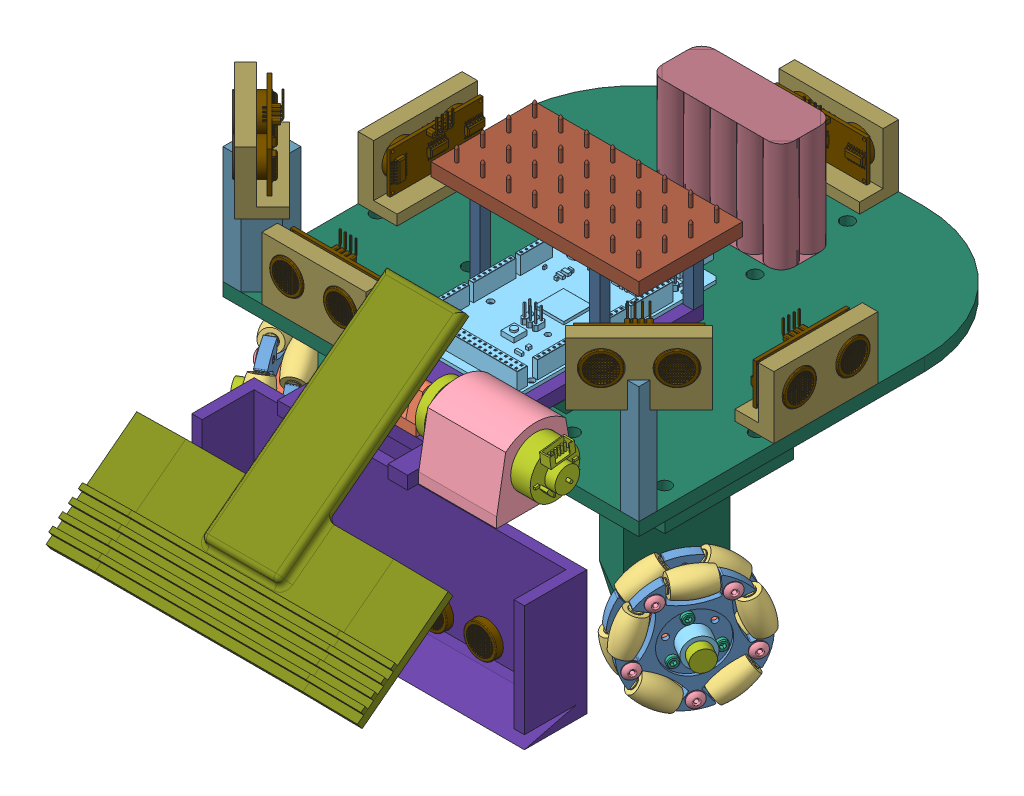
SolidWorks assembly Final_Assem_v2, configuration Default. Lengths in mm.
Overall size (261.62 184.22 333.49).
163 component instances, 35 part files, 105 mates.
Components (placement in the parent):
- WheelAsm-1: WheelAsm [Default] at (163.9905 -186.0529 158.5442) x (-0.148791 -0.954696 0.257713) z (-0.866025 0 -0.5) size (63.86 60.79 27.6)
  - WheelBase-2: WheelBase [Default] at (4.9023 2.731 55.3836) x (1 0 0) z (0 -1 0) size (56.86 5 54.96)
  - BasePlacer-1: BasePlacer [Default] at (4.9023 2.731 58.8836) x (1 0 0) z (0 -1 0) size (28 10 28)
  - RubberWheel-1: RubberWheel [Default] at (4.9023 26.7901 57.8836) x (1 0 0) z (0 -0.999594 -0.028494) size (19 12.5 12.5)
  - RubberWheel-2: RubberWheel [Default] at (-17.9792 10.1657 57.8836) x (0.309017 0.951057 0) z (0.95067 -0.308892 -0.028494) size (19 12.5 12.5)
  - RubberWheel-3: RubberWheel [Default] at (-9.2392 -16.7332 57.8836) x (-0.809017 0.587785 0) z (0.587547 0.808689 -0.028494) size (19 12.5 12.5)
  - RubberWheel-4: RubberWheel [Default] at (19.0439 -16.7332 57.8836) x (-0.809017 -0.587785 0) z (-0.587547 0.808689 -0.028494) size (19 12.5 12.5)
  - RubberWheel-5: RubberWheel [Default] at (27.7839 10.1657 57.8836) x (0.309017 -0.951057 0) z (-0.95067 -0.308892 -0.028494) size (19 12.5 12.5)
  - Rivet-1: Rivet [Default] at (4.9023 -21.269 54.8836) x (1 0 0) z (0 1 0) size (7.46 6.8 7.46)
  - Rivet-2: Rivet [Default] at (27.7277 -4.6854 54.8836) x (0.309017 0.951057 0) z (-0.951057 0.309017 0) size (7.46 6.8 7.46)
  - Rivet-3: Rivet [Default] at (19.0092 22.1474 54.8836) x (-0.809017 0.587785 0) z (-0.587785 -0.809017 0) size (7.46 6.8 7.46)
  - Rivet-4: Rivet [Default] at (-9.2045 22.1474 54.8836) x (-0.809017 -0.587785 0) z (0.587785 -0.809017 0) size (7.46 6.8 7.46)
  - Rivet-5: Rivet [Default] at (-17.923 -4.6854 54.8836) x (0.309017 -0.951057 0) z (0.951057 0.309017 0) size (7.46 6.8 7.46)
  - WheelBase-6: WheelBase [Default] at (4.9023 2.731 67.3836) x (-1 0 0) z (0 1 0) size (56.86 5 54.96)
  - RubberWheel-16: RubberWheel [Default] at (4.9023 -21.3281 69.8836) size (19 12.5 12.5)
  - RubberWheel-17: RubberWheel [Default] at (27.7839 -4.7037 69.8836) x (0.309017 0.951057 0) z (0 0 1) size (19 12.5 12.5)
  - RubberWheel-18: RubberWheel [Default] at (19.0439 22.1953 69.8836) x (-0.809017 0.587785 0) z (0 0 1) size (19 12.5 12.5)
  - RubberWheel-19: RubberWheel [Default] at (-9.2392 22.1953 69.8836) x (-0.809017 -0.587785 0) z (0 0 1) size (19 12.5 12.5)
  - RubberWheel-20: RubberWheel [Default] at (-17.9792 -4.7037 69.8836) x (0.309017 -0.951057 0) z (0 0 1) size (19 12.5 12.5)
  - Rivet-16: Rivet [Default] at (-9.2045 -16.6854 72.8836) x (-0.985624 0.168955 0) z (0.168955 0.985624 0) size (7.46 6.8 7.46)
  - Rivet-17: Rivet [Default] at (19.0092 -16.6854 72.8836) x (-0.46526 -0.885174 0) z (-0.885174 0.46526 0) size (7.46 6.8 7.46)
  - Rivet-18: Rivet [Default] at (27.7277 10.1474 72.8836) x (0.698077 -0.716022 0) z (-0.716022 -0.698077 0) size (7.46 6.8 7.46)
  - Rivet-19: Rivet [Default] at (4.9023 26.731 72.8836) x (0.896695 0.442648 0) z (0.442648 -0.896695 0) size (7.46 6.8 7.46)
  - Rivet-20: Rivet [Default] at (-17.923 10.1474 72.8836) x (-0.143889 0.989594 0) z (0.989594 0.143889 0) size (7.46 6.8 7.46)
  - ShaftConnector-1: ShaftConnector [Default] at (4.9023 2.731 48.8836) x (1 0 0) z (0 -1 0) size (14 27.6 14)
  - Part7^WheelAsm-1: Part7^WheelAsm [Default] at origin (virtual)
  - Part8^WheelAsm-1: Part8^WheelAsm [Default] at origin (virtual)
  - M3HexNut-1: M3HexNut [Default] at (13.9956 7.981 72.8836) x (1 0 0) z (0 0 -1) size (5 5 5)
  - M3HexNut-2: M3HexNut [Default] at (-4.1909 7.981 72.8836) x (-0.5 0.866025 0) z (0 0 -1) size (5 5 5)
  - M3HexNut-3: M3HexNut [Default] at (4.9023 -7.769 72.8836) x (-0.5 -0.866025 0) z (0 0 -1) size (5 5 5)
  - M3HexNut-4: M3HexNut [Default] at (4.9023 -7.769 54.8836) size (5 5 5)
  - M3HexNut-5: M3HexNut [Default] at (13.9956 7.981 54.8836) x (-0.5 0.866025 0) z (0 0 1) size (5 5 5)
  - M3HexNut-6: M3HexNut [Default] at (-4.1909 7.981 54.8836) x (-0.5 -0.866025 0) z (0 0 1) size (5 5 5)
- WheelAsm-2: WheelAsm [Default] at (14.2994 -187.213 -102.2458) x (-0.999988 0.004806 0) z (0 0 1) size (63.86 60.79 27.6)
  - WheelBase-2: WheelBase [Default] at (4.9023 2.731 55.3836) x (1 0 0) z (0 -1 0) size (56.86 5 54.96)
  - BasePlacer-1: BasePlacer [Default] at (4.9023 2.731 58.8836) x (1 0 0) z (0 -1 0) size (28 10 28)
  - RubberWheel-1: RubberWheel [Default] at (4.9023 26.7901 57.8836) x (1 0 0) z (0 -0.999594 -0.028494) size (19 12.5 12.5)
  - RubberWheel-2: RubberWheel [Default] at (-17.9792 10.1657 57.8836) x (0.309017 0.951057 0) z (0.95067 -0.308892 -0.028494) size (19 12.5 12.5)
  - RubberWheel-3: RubberWheel [Default] at (-9.2392 -16.7332 57.8836) x (-0.809017 0.587785 0) z (0.587547 0.808689 -0.028494) size (19 12.5 12.5)
  - RubberWheel-4: RubberWheel [Default] at (19.0439 -16.7332 57.8836) x (-0.809017 -0.587785 0) z (-0.587547 0.808689 -0.028494) size (19 12.5 12.5)
  - RubberWheel-5: RubberWheel [Default] at (27.7839 10.1657 57.8836) x (0.309017 -0.951057 0) z (-0.95067 -0.308892 -0.028494) size (19 12.5 12.5)
  - Rivet-1: Rivet [Default] at (4.9023 -21.269 54.8836) x (1 0 0) z (0 1 0) size (7.46 6.8 7.46)
  - Rivet-2: Rivet [Default] at (27.7277 -4.6854 54.8836) x (0.309017 0.951057 0) z (-0.951057 0.309017 0) size (7.46 6.8 7.46)
  - Rivet-3: Rivet [Default] at (19.0092 22.1474 54.8836) x (-0.809017 0.587785 0) z (-0.587785 -0.809017 0) size (7.46 6.8 7.46)
  - Rivet-4: Rivet [Default] at (-9.2045 22.1474 54.8836) x (-0.809017 -0.587785 0) z (0.587785 -0.809017 0) size (7.46 6.8 7.46)
  - Rivet-5: Rivet [Default] at (-17.923 -4.6854 54.8836) x (0.309017 -0.951057 0) z (0.951057 0.309017 0) size (7.46 6.8 7.46)
  - WheelBase-6: WheelBase [Default] at (4.9023 2.731 67.3836) x (-1 0 0) z (0 1 0) size (56.86 5 54.96)
  - RubberWheel-16: RubberWheel [Default] at (4.9023 -21.3281 69.8836) size (19 12.5 12.5)
  - RubberWheel-17: RubberWheel [Default] at (27.7839 -4.7037 69.8836) x (0.309017 0.951057 0) z (0 0 1) size (19 12.5 12.5)
  - RubberWheel-18: RubberWheel [Default] at (19.0439 22.1953 69.8836) x (-0.809017 0.587785 0) z (0 0 1) size (19 12.5 12.5)
  - RubberWheel-19: RubberWheel [Default] at (-9.2392 22.1953 69.8836) x (-0.809017 -0.587785 0) z (0 0 1) size (19 12.5 12.5)
  - RubberWheel-20: RubberWheel [Default] at (-17.9792 -4.7037 69.8836) x (0.309017 -0.951057 0) z (0 0 1) size (19 12.5 12.5)
  - Rivet-16: Rivet [Default] at (-9.2045 -16.6854 72.8836) x (-0.985624 0.168955 0) z (0.168955 0.985624 0) size (7.46 6.8 7.46)
  - Rivet-17: Rivet [Default] at (19.0092 -16.6854 72.8836) x (-0.46526 -0.885174 0) z (-0.885174 0.46526 0) size (7.46 6.8 7.46)
  - Rivet-18: Rivet [Default] at (27.7277 10.1474 72.8836) x (0.698077 -0.716022 0) z (-0.716022 -0.698077 0) size (7.46 6.8 7.46)
  - Rivet-19: Rivet [Default] at (4.9023 26.731 72.8836) x (0.896695 0.442648 0) z (0.442648 -0.896695 0) size (7.46 6.8 7.46)
  - Rivet-20: Rivet [Default] at (-17.923 10.1474 72.8836) x (-0.143889 0.989594 0) z (0.989594 0.143889 0) size (7.46 6.8 7.46)
  - ShaftConnector-1: ShaftConnector [Default] at (4.9023 2.731 48.8836) x (1 0 0) z (0 -1 0) size (14 27.6 14)
  - Part7^WheelAsm-1: Part7^WheelAsm [Default] at origin (virtual)
  - Part8^WheelAsm-1: Part8^WheelAsm [Default] at origin (virtual)
  - M3HexNut-1: M3HexNut [Default] at (13.9956 7.981 72.8836) x (1 0 0) z (0 0 -1) size (5 5 5)
  - M3HexNut-2: M3HexNut [Default] at (-4.1909 7.981 72.8836) x (-0.5 0.866025 0) z (0 0 -1) size (5 5 5)
  - M3HexNut-3: M3HexNut [Default] at (4.9023 -7.769 72.8836) x (-0.5 -0.866025 0) z (0 0 -1) size (5 5 5)
  - M3HexNut-4: M3HexNut [Default] at (4.9023 -7.769 54.8836) size (5 5 5)
  - M3HexNut-5: M3HexNut [Default] at (13.9956 7.981 54.8836) x (-0.5 0.866025 0) z (0 0 1) size (5 5 5)
  - M3HexNut-6: M3HexNut [Default] at (-4.1909 7.981 54.8836) x (-0.5 -0.866025 0) z (0 0 1) size (5 5 5)
- WheelAsm-3: WheelAsm [Default] at (-145.8609 -191.8955 157.5426) x (0.323209 0.762983 0.559814) z (0.866025 0 -0.5) size (63.86 60.79 27.6)
  - WheelBase-2: WheelBase [Default] at (4.9023 2.731 55.3836) x (1 0 0) z (0 -1 0) size (56.86 5 54.96)
  - BasePlacer-1: BasePlacer [Default] at (4.9023 2.731 58.8836) x (1 0 0) z (0 -1 0) size (28 10 28)
  - RubberWheel-1: RubberWheel [Default] at (4.9023 26.7901 57.8836) x (1 0 0) z (0 -0.999594 -0.028494) size (19 12.5 12.5)
  - RubberWheel-2: RubberWheel [Default] at (-17.9792 10.1657 57.8836) x (0.309017 0.951057 0) z (0.95067 -0.308892 -0.028494) size (19 12.5 12.5)
  - RubberWheel-3: RubberWheel [Default] at (-9.2392 -16.7332 57.8836) x (-0.809017 0.587785 0) z (0.587547 0.808689 -0.028494) size (19 12.5 12.5)
  - RubberWheel-4: RubberWheel [Default] at (19.0439 -16.7332 57.8836) x (-0.809017 -0.587785 0) z (-0.587547 0.808689 -0.028494) size (19 12.5 12.5)
  - RubberWheel-5: RubberWheel [Default] at (27.7839 10.1657 57.8836) x (0.309017 -0.951057 0) z (-0.95067 -0.308892 -0.028494) size (19 12.5 12.5)
  - Rivet-1: Rivet [Default] at (4.9023 -21.269 54.8836) x (1 0 0) z (0 1 0) size (7.46 6.8 7.46)
  - Rivet-2: Rivet [Default] at (27.7277 -4.6854 54.8836) x (0.309017 0.951057 0) z (-0.951057 0.309017 0) size (7.46 6.8 7.46)
  - Rivet-3: Rivet [Default] at (19.0092 22.1474 54.8836) x (-0.809017 0.587785 0) z (-0.587785 -0.809017 0) size (7.46 6.8 7.46)
  - Rivet-4: Rivet [Default] at (-9.2045 22.1474 54.8836) x (-0.809017 -0.587785 0) z (0.587785 -0.809017 0) size (7.46 6.8 7.46)
  - Rivet-5: Rivet [Default] at (-17.923 -4.6854 54.8836) x (0.309017 -0.951057 0) z (0.951057 0.309017 0) size (7.46 6.8 7.46)
  - WheelBase-6: WheelBase [Default] at (4.9023 2.731 67.3836) x (-1 0 0) z (0 1 0) size (56.86 5 54.96)
  - RubberWheel-16: RubberWheel [Default] at (4.9023 -21.3281 69.8836) size (19 12.5 12.5)
  - RubberWheel-17: RubberWheel [Default] at (27.7839 -4.7037 69.8836) x (0.309017 0.951057 0) z (0 0 1) size (19 12.5 12.5)
  - RubberWheel-18: RubberWheel [Default] at (19.0439 22.1953 69.8836) x (-0.809017 0.587785 0) z (0 0 1) size (19 12.5 12.5)
  - RubberWheel-19: RubberWheel [Default] at (-9.2392 22.1953 69.8836) x (-0.809017 -0.587785 0) z (0 0 1) size (19 12.5 12.5)
  - RubberWheel-20: RubberWheel [Default] at (-17.9792 -4.7037 69.8836) x (0.309017 -0.951057 0) z (0 0 1) size (19 12.5 12.5)
  - Rivet-16: Rivet [Default] at (-9.2045 -16.6854 72.8836) x (-0.985624 0.168955 0) z (0.168955 0.985624 0) size (7.46 6.8 7.46)
  - Rivet-17: Rivet [Default] at (19.0092 -16.6854 72.8836) x (-0.46526 -0.885174 0) z (-0.885174 0.46526 0) size (7.46 6.8 7.46)
  - Rivet-18: Rivet [Default] at (27.7277 10.1474 72.8836) x (0.698077 -0.716022 0) z (-0.716022 -0.698077 0) size (7.46 6.8 7.46)
  - Rivet-19: Rivet [Default] at (4.9023 26.731 72.8836) x (0.896695 0.442648 0) z (0.442648 -0.896695 0) size (7.46 6.8 7.46)
  - Rivet-20: Rivet [Default] at (-17.923 10.1474 72.8836) x (-0.143889 0.989594 0) z (0.989594 0.143889 0) size (7.46 6.8 7.46)
  - ShaftConnector-1: ShaftConnector [Default] at (4.9023 2.731 48.8836) x (1 0 0) z (0 -1 0) size (14 27.6 14)
  - Part7^WheelAsm-1: Part7^WheelAsm [Default] at origin (virtual)
  - Part8^WheelAsm-1: Part8^WheelAsm [Default] at origin (virtual)
  - M3HexNut-1: M3HexNut [Default] at (13.9956 7.981 72.8836) x (1 0 0) z (0 0 -1) size (5 5 5)
  - M3HexNut-2: M3HexNut [Default] at (-4.1909 7.981 72.8836) x (-0.5 0.866025 0) z (0 0 -1) size (5 5 5)
  - M3HexNut-3: M3HexNut [Default] at (4.9023 -7.769 72.8836) x (-0.5 -0.866025 0) z (0 0 -1) size (5 5 5)
  - M3HexNut-4: M3HexNut [Default] at (4.9023 -7.769 54.8836) size (5 5 5)
  - M3HexNut-5: M3HexNut [Default] at (13.9956 7.981 54.8836) x (-0.5 0.866025 0) z (0 0 1) size (5 5 5)
  - M3HexNut-6: M3HexNut [Default] at (-4.1909 7.981 54.8836) x (-0.5 -0.866025 0) z (0 0 1) size (5 5 5)
- 6V Motor Spin-1: 6V Motor Spin [Default] at (27.2733 -240.3712 40.8764) x (-0.886104 0.457845 -0.072098) z (0.080946 -0.000295 -0.996718) size (29.63 28.32 78.39)
  - Motor no spinny boi-1: Motor no spinny boi [Default] at (39.6165 36.3483 7.7453) x (0.997226 -0.015871 -0.072721) z (0.072098 -0.036799 0.996718) size (24.4 25.49 66.9)
  - Motor spinny boi-1: Motor spinny boi [Default] at (39.6165 36.3483 7.7453) x (0.547957 0.836461 -0.008754) z (0.072098 -0.036799 0.996718) size (3.95 3.95 13.05)
- DC Motor 12V-1: DC Motor 12V [Predeterminado] at (-53.9561 -189.9205 110.5467) x (0.5 0 0.866025) z (-0.866025 0 0.5) size (28.03 28 53.5)
  - Carcaça12V-1: Carcaça12V [Predeterminado] at (0 0 24.0663) size (28.03 28 32.04)
  - Bucha12V-1: Bucha12V [Predeterminado] at (0 0 26.0163) x (0.994754 0.102295 0) z (0 0 1) size (7 7 0.5)
  - Mancal12V-1: Mancal12V [Predeterminado] at (0 0 -2.9337) x (-1 0 0) z (0 0 -1) size (27.69 28 8)
  - Terminal12V-1: Terminal12V [Predeterminado] at (0 -11.5 -3.9337) x (1 0 0) z (0 1 0) size (2.9 10 0.4)
  - Terminal12V-2: Terminal12V [Predeterminado] at (0 11.5 -3.9337) x (1 0 0) z (0 1 0) size (2.9 10 0.4)
  - Eixo12V-1: Eixo12V [Predeterminado] at (0 0 39.5663) x (-0.33009 -0.943949 0) z (0 0 1) size (21 20.89 51)
  - Enrolamento12V-1: Enrolamento12V [Predeterminado] at (-5.1702 1.808 12.5663) x (0.33009 0.943949 0) z (0 0 1) size (10 3 20)
  - Enrolamento12V-2: Enrolamento12V [Predeterminado] at (1.0194 -5.3815 12.5663) x (-0.982529 -0.186108 0) z (0 0 1) size (10 3 20)
  - Enrolamento12V-3: Enrolamento12V [Predeterminado] at (4.1509 3.5736 12.5663) x (0.652439 -0.757841 0) z (0 0 1) size (10 3 20)
- DC Motor 12V-2: DC Motor 12V [Predeterminado] at (72.7137 -189.9205 110.5407) x (-0.212518 0.905176 0.368092) z (0.866025 0 0.5) size (28.03 28 53.5)
  - Carcaça12V-1: Carcaça12V [Predeterminado] at (0 0 24.0663) size (28.03 28 32.04)
  - Bucha12V-1: Bucha12V [Predeterminado] at (0 0 26.0163) x (0.994754 0.102295 0) z (0 0 1) size (7 7 0.5)
  - Mancal12V-1: Mancal12V [Predeterminado] at (0 0 -2.9337) x (-1 0 0) z (0 0 -1) size (27.69 28 8)
  - Terminal12V-1: Terminal12V [Predeterminado] at (0 -11.5 -3.9337) x (1 0 0) z (0 1 0) size (2.9 10 0.4)
  - Terminal12V-2: Terminal12V [Predeterminado] at (0 11.5 -3.9337) x (1 0 0) z (0 1 0) size (2.9 10 0.4)
  - Eixo12V-1: Eixo12V [Predeterminado] at (0 0 39.5663) x (-0.33009 -0.943949 0) z (0 0 1) size (21 20.89 51)
  - Enrolamento12V-1: Enrolamento12V [Predeterminado] at (-5.1702 1.808 12.5663) x (0.33009 0.943949 0) z (0 0 1) size (10 3 20)
  - Enrolamento12V-2: Enrolamento12V [Predeterminado] at (1.0194 -5.3815 12.5663) x (-0.982529 -0.186108 0) z (0 0 1) size (10 3 20)
  - Enrolamento12V-3: Enrolamento12V [Predeterminado] at (4.1509 3.5736 12.5663) x (0.652439 -0.757841 0) z (0 0 1) size (10 3 20)
- Acrylic Plate (square 12 inch) cut version-1: Acrylic Plate (square 12 inch) cut version [Default] at (9.384 -134.5485 57.0478) size (203.2 6.35 203.2)
- ScoopClawAssembly-1: ScoopClawAssembly [Default] at (-135.2234 -155.5644 109.464) size (171.3 138.74 218)
  - Scooper-1: Scooper [Default] at (144.6073 0.6103 138.0053) x (1 0 0) z (0 0.793599 0.608442) size (152.65 142.24 11.1)
  - Scooper_Base-1: Scooper_Base [Default] at (144.6073 -61.534 72.0438) size (162.56 95.25 144.78)
  - HC-SR04-UltrasonicSensor v7-2: HC-SR04-UltrasonicSensor v7 [Default] at (144.5683 -48.834 48.9638) x (-1 0 0) z (0 0 1) size (45.45 26.2 17.79)
  - Hinge_Joint-1: Hinge_Joint [Default] at (126.8273 46.416 67.8239) x (0 0.774266 0.63286) z (1 0 0) size (8.89 8.89 40.64)
  - Hinge_Part1-1: Hinge_Part1 [Default] at (144.6073 33.716 67.8239) size (35.56 18.62 12.7)
  - Hinge_Part2-1: Hinge_Part2 [Default] at (144.6073 54.4789 74.0056) x (1 0 0) z (0 0.608442 -0.793599) size (25.4 16.08 12.7)
  - 6V Motor Spin-1: 6V Motor Spin [Default] at (231.6559 14.0419 25.1949) x (-0.072098 -0.103157 0.992049) z (-0.996718 0.044149 -0.067847) size (29.63 28.32 78.39)
    - Motor no spinny boi-1: Motor no spinny boi [Default] at (39.6165 36.3483 7.7453) x (0.997226 -0.015871 -0.072721) z (0.072098 -0.036799 0.996718) size (24.4 25.49 66.9)
    - Motor spinny boi-1: Motor spinny boi [Default] at (39.6165 36.3483 7.7453) x (0.547957 0.836461 -0.008754) z (0.072098 -0.036799 0.996718) size (3.95 3.95 13.05)
  - Motor Support-1: Motor Support [Default] at (195.4073 27.366 67.8239) size (38.1 54.53 38.1)
- ArduinoMega-1: ArduinoMega [Default] at (9.3459 -119.6895 95.1478) x (0 0 -1) z (0 -1 0) size (107.95 53.42 12.95)
- 12V Motor Support -Right-2: 12V Motor Support -Right [Default] at (-60.72 -189.9205 114.4518) x (0.866025 0 -0.5) z (0.5 0 0.866025) size (86.05 74.11 86.05)
- OmniWheel_Connection Piece-2: OmniWheel_Connection Piece [Default] at (95.4263 -189.9205 123.6538) x (-0.490726 0.19171 0.849962) z (0.866025 0 0.5) size (10.16 10.16 33.02)
- OmniWheel_Connection Piece-3: OmniWheel_Connection Piece [Default] at (-76.7034 -189.9205 123.6798) x (0.5 0 0.866025) z (-0.866025 0 0.5) size (10.16 10.16 33.02)
- 6V Motor Support-1: 6V Motor Support [Default] at (9.384 -189.9205 2.4378) x (0 0 -1) z (1 0 0) size (57.91 74.11 63.5)
- 6V Wheel Connector-1: 6V Wheel Connector [Default] at (9.384 -189.9205 -26.1842) x (-0.104526 0.994522 0) z (0 0 -1) size (10.16 10.16 32.26)
- LED Height Booster-1: LED Height Booster [Default] at (38.594 -83.7485 59.5878) x (-1 0 0) z (0 0 1) size (5.08 38.1 5.08)
- LED Height Booster-2: LED Height Booster [Default] at (-19.826 -121.8485 105.3042) size (5.08 38.1 5.08)
- LED Height Booster-3: LED Height Booster [Default] at (38.594 -83.7485 105.3042) x (-1 0 0) z (0 0 1) size (5.08 38.1 5.08)
- LED Height Booster-4: LED Height Booster [Default] at (-19.826 -121.8485 59.5878) size (5.08 38.1 5.08)
- LightBoard Localization-2: LightBoard Localization [Default] at (9.384 -83.7485 82.4478) x (-1 0 0) z (0 0 -1) size (101.6 13.49 50.8)
- HC-SR04-UltrasonicSensor v7-1: HC-SR04-UltrasonicSensor v7 [Default] at (-40.996 -204.3985 158.4278) x (-1 0 0) z (0 0 1) size (45.45 26.2 17.79)
- HC-SR04-UltrasonicSensor v7-2: HC-SR04-UltrasonicSensor v7 [Default] at (59.764 -204.3985 158.4278) x (-1 0 0) z (0 0 1) size (45.45 26.2 17.79)
- US_Support-2: US_Support [Default] at (103.364 -123.1185 67.2078) x (0 0 -1) z (1 0 0) size (50.8 30.48 19.05)
- US_Support-3: US_Support [Default] at (-84.596 -123.1185 67.2078) x (0 0 1) z (-1 0 0) size (50.8 30.48 19.05)
- BatteryRemodeled-2: BatteryRemodeled [Default] at (34.784 -76.1031 -0.1022) x (-1 0 0) z (0 0 1) size (64.52 53.39 25.65)
- US_Support-4: US_Support [Default] at (9.384 -123.1185 -36.9322) x (-1 0 0) z (0 0 -1) size (50.8 30.48 19.05)
- US_Support-5: US_Support [Default] at (-47.766 -123.1185 151.0278) size (50.8 30.48 19.05)
- HC-SR04-UltrasonicSensor v7-3: HC-SR04-UltrasonicSensor v7 [Default] at (98.064 -110.4185 67.1688) x (0 0 1) z (1 0 0) size (45.45 26.2 17.79)
- HC-SR04-UltrasonicSensor v7-4: HC-SR04-UltrasonicSensor v7 [Default] at (9.345 -110.4185 -31.6322) x (1 0 0) z (0 0 -1) size (45.45 26.2 17.79)
- HC-SR04-UltrasonicSensor v7-5: HC-SR04-UltrasonicSensor v7 [Default] at (-79.296 -110.4185 67.1688) x (0 0 -1) z (-1 0 0) size (45.45 26.2 17.79)
- corner_support-1: corner_support [Default] at (-82.691 -128.1985 149.1228) size (19.05 57.15 19.05)
- US_Support-6: US_Support [Default] at (-84.1338 -78.6685 150.386) x (0.707107 0 0.707107) z (-0.707107 0 0.707107) size (50.8 30.48 19.05)
- HC-SR04-UltrasonicSensor v7-6: HC-SR04-UltrasonicSensor v7 [Default] at (-80.3586 -65.9685 146.6659) x (-0.707107 0 -0.707107) z (-0.707107 0 0.707107) size (45.45 26.2 17.79)
- HC-SR04-UltrasonicSensor v7-7: HC-SR04-UltrasonicSensor v7 [Default] at (-47.805 -110.4185 145.7278) x (-1 0 0) z (0 0 1) size (45.45 26.2 17.79)
- corner_support-2: corner_support [Default] at (101.459 -128.1985 149.1228) x (0 0 -1) z (1 0 0) size (19.05 57.15 19.05)
- US_Support-7: US_Support [Default] at (102.9017 -78.6685 150.386) x (0.707107 0 -0.707107) z (0.707107 0 0.707107) size (50.8 30.48 19.05)
- HC-SR04-UltrasonicSensor v7-8: HC-SR04-UltrasonicSensor v7 [Default] at (99.1265 -65.9685 146.6659) x (-0.707107 0 0.707107) z (0.707107 0 0.707107) size (45.45 26.2 17.79)
- 12V Motor Support - Left-1: 12V Motor Support - Left [Default] at (79.488 -189.9205 114.4518) x (0.866025 0 0.5) z (-0.5 0 0.866025) size (86.05 74.11 86.05)
Mates (geometry in assembly coordinates):
- Coincident3: coincident: plane of Acrylic Plate (square 12 inch) cut version-1 through (9.384 -128.1985 57.0478) normal (0 1 0); plane of ScoopClawAssembly-1/Scooper_Base-1 through (9.384 -128.1985 181.5078) normal (0 -1 0)
- Coincident4: coincident: plane of Acrylic Plate (square 12 inch) cut version-1 through (-92.216 -128.1985 158.6478) normal (0 0 1); plane of ScoopClawAssembly-1/Scooper_Base-1 through (9.384 -217.0985 158.6478) normal (0 0 -1)
- Distance4: distance = 0.508 mm: plane of ScoopClawAssembly-1/Scooper_Base-1 through (9.384 -121.8485 181.5078) normal (0 1 0); plane of ArduinoMega-1 through (-17.3622 -121.3405 44.3478) normal (0 -1 0)
- Distance6: distance = 12.7 mm: plane of ArduinoMega-1 through (36.054 -121.3405 44.3478) normal (0 0 -1); plane of ScoopClawAssembly-1/Scooper_Base-1 through (41.134 -121.8485 57.0478) normal (0 0 -1)
- Distance7: distance = 5.08 mm: plane of ArduinoMega-1 through (36.054 -121.3405 145.9478) normal (1 0 0); plane of ScoopClawAssembly-1/Scooper_Base-1 through (41.134 -166.2985 158.6478) normal (1 0 0)
- Coincident23: coincident: plane of Acrylic Plate (square 12 inch) cut version-1 through (9.384 -134.5485 57.0478) normal (0 -1 0); plane of ? through (146.5657 -134.5485 103.1381) normal (0 1 0)
- Coincident29: coincident: plane of Acrylic Plate (square 12 inch) cut version-1 through (9.384 -134.5485 57.0478) normal (0 -1 0); plane of 12V Motor Support -Right-2 through (-60.72 -134.5485 114.4518) normal (0 1 0)
- Concentric1: concentric: cylinder of DC Motor 12V-1/Carcaça12V-1 through (-49.6834 -189.9205 108.0798) axis (-0.866025 0 0.5) radius 14; cylinder of 12V Motor Support -Right-2 through (-156.6272 -189.9205 169.8238) axis (0.866025 0 -0.5) radius 13.9872
- Coincident31: coincident: plane of DC Motor 12V-1/Carcaça12V-1 through (-74.7981 -189.9205 122.5798) normal (-0.866025 0 0.5); plane of 12V Motor Support -Right-2 through (-65.2731 -139.6285 139.0776) normal (-0.866025 0 0.5)
- Coincident32: coincident: plane of DC Motor 12V-2/Carcaça12V-1; plane of ? through (144.59 -139.6285 128.1032) normal (0.707107 0 0.707107)
- Concentric2: concentric: cylinder of DC Motor 12V-2/Carcaça12V-1 through (137.5543 -189.9205 94.1267) axis (0.707107 0 0.707107) radius 14; cylinder of ? through (68.2578 -189.9205 24.8302) axis (0.707107 0 0.707107) radius 13.9872
- Concentric4: concentric: circle of WheelAsm-1/ShaftConnector-1; circle of DC Motor 12V-2/Eixo12V-1
- Coincident36: coincident: plane of WheelAsm-1/ShaftConnector-1 through (95.7207 -189.9205 123.8238) normal (-0.866025 0 -0.5); plane of DC Motor 12V-2/Carcaça12V-1 through (95.7207 -189.9205 123.8238) normal (0.866025 0 0.5)
- Concentric8: concentric: circle of WheelAsm-1/ShaftConnector-1; circle of OmniWheel_Connection Piece-2
- Coincident39: coincident: plane of WheelAsm-1/ShaftConnector-1 through (119.623 -189.9205 137.6238) normal (0.866025 0 0.5); plane of OmniWheel_Connection Piece-2 through (119.623 -189.9205 137.6238) normal (-0.866025 0 -0.5)
- Distance9: distance = 69.85 mm: plane of ScoopClawAssembly-1/Scooper_Base-1 through (-22.366 -128.1985 158.6478) normal (-1 0 0); plane of Acrylic Plate (square 12 inch) cut version-1 through (-92.216 -128.1985 158.6478) normal (-1 0 0)
- Concentric9: concentric: circle of WheelAsm-3/ShaftConnector-1; circle of DC Motor 12V-1/Eixo12V-1
- Coincident42: coincident: plane of WheelAsm-3/ShaftConnector-1 through (-100.9002 -189.9205 137.6498) normal (-0.866025 0 0.5); plane of OmniWheel_Connection Piece-3 through (-100.9002 -189.9205 137.6498) normal (0.866025 0 -0.5)
- Concentric10: concentric: circle of WheelAsm-3/ShaftConnector-1; circle of OmniWheel_Connection Piece-3
- Coincident43: coincident: plane of DC Motor 12V-1/Bucha12V-1 through (-76.7034 -189.9205 123.6798) normal (-0.866025 0 0.5); plane of OmniWheel_Connection Piece-3 through (-76.7034 -189.9205 123.6798) normal (0.866025 0 -0.5)
- Coincident45: coincident: plane of Acrylic Plate (square 12 inch) cut version-1 through (9.384 -134.5485 57.0478) normal (0 -1 0); plane of 6V Motor Support-1 through (9.384 -134.5485 2.4378) normal (0 1 0)
- Concentric11: concentric: circle of 6V Motor Spin-1/Motor no spinny boi-1; circle of 6V Motor Support-1
- Coincident48: coincident: plane of 6V Motor Spin-1/Motor no spinny boi-1 through (9.384 -189.9205 -22.9622) normal (0 0 -1); plane of 6V Motor Support-1 through (28.434 -139.6285 -22.9622) normal (0 0 -1)
- Concentric13: concentric: circle of WheelAsm-2/ShaftConnector-1; circle of 6V Motor Support-1
- Coincident49: coincident: plane of WheelAsm-2/ShaftConnector-1 through (9.384 -189.9205 -25.7622) normal (0 0 1); plane of 6V Motor Spin-1/Motor no spinny boi-1 through (9.384 -189.9205 -25.7622) normal (0 0 -1)
- Concentric14: concentric: circle of WheelAsm-2/ShaftConnector-1; circle of 6V Wheel Connector-1
- Coincident51: coincident: plane of 6V Motor Spin-1/Motor spinny boi-1 through (9.2246 -188.4038 -26.0122) normal (-0.104526 0.994522 0); plane of 6V Wheel Connector-1 through (9.2246 -188.4038 -36.0902) normal (0.104526 -0.994522 0)
- Coincident52: coincident: plane of WheelAsm-2/ShaftConnector-1 through (9.384 -189.9205 -53.3622) normal (0 0 -1); plane of 6V Wheel Connector-1 through (9.384 -189.9205 -53.3622) normal (0 0 1)
- Distance13: distance = 18.034 mm: plane of 6V Motor Support-1 through (41.134 -134.5485 -26.5182) normal (0 0 -1); plane of Acrylic Plate (square 12 inch) cut version-1 through (-92.216 -128.1985 -44.5522) normal (0 0 -1)
- Distance15: distance = 69.85 mm: plane of 6V Motor Support-1 through (41.134 -134.5485 -26.5182) normal (1 0 0); plane of Acrylic Plate (square 12 inch) cut version-1 through (110.984 -128.1985 158.6478) normal (1 0 0)
- Coincident73: coincident: plane of ScoopClawAssembly-1/Scooper_Base-1 through (9.384 -121.8485 181.5078) normal (0 1 0); plane of LED Height Booster-1 through (38.594 -121.8485 59.5878) normal (0 -1 0)
- Coincident74: coincident: plane of ScoopClawAssembly-1/Scooper_Base-1 through (41.134 -121.8485 57.0478) normal (0 0 -1); plane of LED Height Booster-1 through (41.134 -121.8485 57.0478) normal (0 0 -1)
- Coincident75: coincident: plane of ScoopClawAssembly-1/Scooper_Base-1 through (41.134 -166.2985 158.6478) normal (1 0 0); plane of LED Height Booster-1 through (41.134 -121.8485 62.1278) normal (1 0 0)
- Coincident76: coincident: plane of ScoopClawAssembly-1/Scooper_Base-1 through (41.134 -121.8485 57.0478) normal (0 0 -1); plane of LED Height Booster-4 through (-22.366 -83.7485 57.0478) normal (0 0 -1)
- Coincident77: coincident: plane of ScoopClawAssembly-1/Scooper_Base-1 through (9.384 -121.8485 181.5078) normal (0 1 0); plane of LED Height Booster-4 through (-19.826 -121.8485 59.5878) normal (0 -1 0)
- Coincident78: coincident: plane of ScoopClawAssembly-1/Scooper_Base-1 through (-22.366 -128.1985 158.6478) normal (-1 0 0); plane of LED Height Booster-4 through (-22.366 -83.7485 62.1278) normal (-1 0 0)
- Coincident79: coincident: plane of ScoopClawAssembly-1/Scooper_Base-1 through (9.384 -121.8485 181.5078) normal (0 1 0); plane of LED Height Booster-3 through (38.594 -121.8485 105.3042) normal (0 -1 0)
- Coincident80: coincident: plane of LED Height Booster-1 through (41.134 -121.8485 62.1278) normal (1 0 0); plane of LED Height Booster-3 through (41.134 -121.8485 107.8442) normal (1 0 0)
- Distance21: distance = 55.4736 mm: plane of LED Height Booster-3 through (41.134 -121.8485 102.7642) normal (0 0 -1); plane of ScoopClawAssembly-1/Motor Support-1 through (41.134 -123.1185 158.2378) normal (0 0 -1)
- Coincident82: coincident: plane of LED Height Booster-2 through (-22.366 -83.7485 102.7642) normal (0 0 -1); plane of LED Height Booster-3 through (41.134 -121.8485 102.7642) normal (0 0 -1)
- Coincident83: coincident: plane of ScoopClawAssembly-1/Scooper_Base-1 through (9.384 -121.8485 181.5078) normal (0 1 0); plane of LED Height Booster-2 through (-19.826 -121.8485 105.3042) normal (0 -1 0)
- Coincident84: coincident: plane of ScoopClawAssembly-1/Scooper_Base-1 through (-22.366 -128.1985 158.6478) normal (-1 0 0); plane of LED Height Booster-2 through (-22.366 -83.7485 107.8442) normal (-1 0 0)
- Coincident85: coincident: plane of LED Height Booster-1 through (38.594 -83.7485 59.5878) normal (0 1 0); plane of LightBoard Localization-2 through (9.384 -83.7485 82.4478) normal (0 -1 0)
- Coincident88: coincident: plane of LED Height Booster-4 through (-22.366 -83.7485 57.0478) normal (0 0 -1); plane of LightBoard Localization-2 through (60.184 -77.3985 57.0478) normal (0 0 -1)
- Distance22: distance = 19.05 mm: plane of LightBoard Localization-2 through (-41.416 -77.3985 57.0478) normal (-1 0 0); plane of LED Height Booster-4 through (-22.366 -83.7485 62.1278) normal (-1 0 0)
- Coincident91: coincident: plane of ScoopClawAssembly-1/Scooper_Base-1 through (9.384 -217.0985 163.7278) normal (0 0 -1); plane of HC-SR04-UltrasonicSensor v7-2 through (59.764 -211.7841 163.7278) normal (0 0 1)
- Parallel9: parallel: plane of ScoopClawAssembly-1/Scooper_Base-1 through (9.384 -217.0985 181.5078) normal (0 -1 0); plane of HC-SR04-UltrasonicSensor v7-2 through (37.039 -214.3985 158.4278) normal (0 -1 0)
- Parallel10: parallel: plane of ScoopClawAssembly-1/Scooper_Base-1 through (9.384 -217.0985 181.5078) normal (0 -1 0); plane of HC-SR04-UltrasonicSensor v7-1 through (-63.721 -214.3985 158.4278) normal (0 -1 0)
- Coincident94: coincident: plane of ScoopClawAssembly-1/Scooper_Base-1 through (9.384 -217.0985 163.7278) normal (0 0 -1); plane of HC-SR04-UltrasonicSensor v7-1 through (-40.996 -211.7841 163.7278) normal (0 0 1)
- Coincident95: coincident: plane of Acrylic Plate (square 12 inch) cut version-1 through (110.984 -128.1985 158.6478) normal (1 0 0); plane of US_Support-2 through (110.984 -123.1185 67.2078) normal (1 0 0)
- Coincident96: coincident: plane of Acrylic Plate (square 12 inch) cut version-1 through (9.384 -128.1985 57.0478) normal (0 1 0); plane of US_Support-2 through (103.364 -128.1985 67.2078) normal (0 -1 0)
- Distance23: distance = 86.36 mm: plane of US_Support-2 through (110.984 -123.1185 41.8078) normal (0 0 -1); plane of Acrylic Plate (square 12 inch) cut version-1 through (-92.216 -128.1985 -44.5522) normal (0 0 -1)
- Coincident98: coincident: plane of US_Support-2 through (110.984 -123.1185 92.6078) normal (0 0 1); plane of US_Support-3 through (-92.216 -123.1185 92.6078) normal (0 0 1)
- Coincident99: coincident: plane of Acrylic Plate (square 12 inch) cut version-1 through (9.384 -128.1985 57.0478) normal (0 1 0); plane of US_Support-3 through (-84.596 -128.1985 67.2078) normal (0 -1 0)
- Coincident100: coincident: plane of Acrylic Plate (square 12 inch) cut version-1 through (-92.216 -128.1985 158.6478) normal (-1 0 0); plane of US_Support-3 through (-92.216 -123.1185 67.2078) normal (-1 0 0)
- Coincident101: coincident: plane of Acrylic Plate (square 12 inch) cut version-1 through (9.384 -128.1985 57.0478) normal (0 1 0); plane of BatteryRemodeled-2 through (34.784 -128.1985 -0.1022) normal (0 -1 0)
- Distance24: distance = 38.1 mm: line of BatteryRemodeled-2 through (-4.078 -128.1731 -6.4522) axis (1 0 0); line of Acrylic Plate (square 12 inch) cut version-1 through (47.484 -128.1985 -44.5522) axis (-1 0 0)
- Distance25: distance = 69.85 mm: line of BatteryRemodeled-2 through (41.134 -128.1731 -0.1022) axis (0 0 1); line of Acrylic Plate (square 12 inch) cut version-1 through (110.984 -128.1985 158.6478) axis (0 0 -1)
- Coincident106: coincident: plane of Acrylic Plate (square 12 inch) cut version-1 through (-92.216 -128.1985 -44.5522) normal (0 0 -1); plane of US_Support-4 through (9.384 -123.1185 -44.5522) normal (0 0 -1)
- Coincident107: coincident: plane of Acrylic Plate (square 12 inch) cut version-1 through (9.384 -128.1985 57.0478) normal (0 1 0); plane of US_Support-4 through (9.384 -128.1985 -36.9322) normal (0 -1 0)
- Distance26: distance = 76.2 mm: plane of US_Support-4 through (-16.016 -123.1185 -44.5522) normal (-1 0 0); plane of Acrylic Plate (square 12 inch) cut version-1 through (-92.216 -128.1985 158.6478) normal (-1 0 0)
- Coincident109: coincident: plane of Acrylic Plate (square 12 inch) cut version-1 through (9.384 -128.1985 57.0478) normal (0 1 0); plane of US_Support-5 through (-47.766 -128.1985 151.0278) normal (0 -1 0)
- Distance27: distance = 19.05 mm: plane of US_Support-5 through (-73.166 -123.1185 158.6478) normal (-1 0 0); plane of Acrylic Plate (square 12 inch) cut version-1 through (-92.216 -128.1985 158.6478) normal (-1 0 0)
- Coincident111: coincident: plane of Acrylic Plate (square 12 inch) cut version-1 through (-92.216 -128.1985 158.6478) normal (0 0 1); plane of US_Support-5 through (-47.766 -123.1185 158.6478) normal (0 0 1)
- Concentric20: concentric: cylinder of HC-SR04-UltrasonicSensor v7-5 through (-80.896 -110.4185 80.2888) axis (-1 0 0) radius 8; cylinder of US_Support-3 through (-92.216 -110.4185 80.2888) axis (1 0 0) radius 8.2697
- Parallel16: parallel: plane of US_Support-3 through (-92.216 -97.7185 41.8078) normal (0 1 0); plane of HC-SR04-UltrasonicSensor v7-5 through (-79.296 -100.4185 89.8938) normal (0 1 0)
- Coincident114: coincident: plane of US_Support-3 through (-84.596 -123.1185 67.2078) normal (1 0 0); plane of HC-SR04-UltrasonicSensor v7-5 through (-84.596 -117.8041 67.1688) normal (-1 0 0)
- Concentric21: concentric: cylinder of US_Support-2 through (110.984 -110.4185 80.2888) axis (-1 0 0) radius 8.2697; cylinder of HC-SR04-UltrasonicSensor v7-3 through (99.664 -110.4185 80.2888) axis (1 0 0) radius 8
- Parallel17: parallel: plane of US_Support-2 through (103.364 -123.1185 67.2078) normal (0 1 0); plane of HC-SR04-UltrasonicSensor v7-3 through (98.064 -120.4185 89.8938) normal (0 -1 0)
- Coincident116: coincident: plane of US_Support-2 through (103.364 -123.1185 67.2078) normal (-1 0 0); plane of HC-SR04-UltrasonicSensor v7-3 through (103.364 -117.8041 67.1688) normal (1 0 0)
- Concentric23: concentric: cylinder of US_Support-4 through (22.465 -110.4185 -44.5522) axis (0 0 1) radius 8.2697; cylinder of HC-SR04-UltrasonicSensor v7-4 through (22.465 -110.4185 -33.2322) axis (0 0 -1) radius 8
- Parallel18: parallel: plane of US_Support-4 through (9.384 -123.1185 -36.9322) normal (0 1 0); plane of HC-SR04-UltrasonicSensor v7-4 through (32.07 -120.4185 -31.6322) normal (0 -1 0)
- Coincident118: coincident: plane of US_Support-4 through (9.384 -123.1185 -36.9322) normal (0 0 1); plane of HC-SR04-UltrasonicSensor v7-4 through (9.345 -117.8041 -36.9322) normal (0 0 -1)
- Coincident119: coincident: plane of Acrylic Plate (square 12 inch) cut version-1 through (-92.216 -128.1985 158.6478) normal (-1 0 0); plane of corner_support-1 through (-92.216 -83.7485 158.6478) normal (-1 0 0)
- Coincident120: coincident: plane of Acrylic Plate (square 12 inch) cut version-1 through (9.384 -128.1985 57.0478) normal (0 1 0); plane of corner_support-1 through (-82.691 -128.1985 149.1228) normal (0 -1 0)
- Coincident121: coincident: plane of Acrylic Plate (square 12 inch) cut version-1 through (-92.216 -128.1985 158.6478) normal (0 0 1); plane of corner_support-1 through (-92.216 -83.7485 158.6478) normal (0 0 1)
- Coincident135: coincident: plane of corner_support-1 through (-86.6483 -71.0485 158.6478) normal (0.707107 0 -0.707107); plane of US_Support-6 through (-89.522 -78.6685 155.7741) normal (-0.707107 0 0.707107)
- Concentric24: concentric: cylinder of US_Support-6 through (-98.7716 -65.9685 146.5245) axis (0.707107 0 -0.707107) radius 8.2697; cylinder of HC-SR04-UltrasonicSensor v7-6 through (-90.7672 -65.9685 138.52) axis (-0.707107 0 0.707107) radius 8
- Parallel23: parallel: plane of US_Support-6 through (-84.1338 -78.6685 150.386) normal (0 1 0); plane of HC-SR04-UltrasonicSensor v7-6 through (-96.4276 -75.9685 130.5969) normal (0 -1 0)
- Coincident138: coincident: plane of US_Support-6 through (-84.1338 -78.6685 150.386) normal (0.707107 0 -0.707107); plane of HC-SR04-UltrasonicSensor v7-6 through (-84.1062 -73.3541 150.4136) normal (-0.707107 0 0.707107)
- Concentric25: concentric: cylinder of US_Support-5 through (-34.685 -110.4185 158.6478) axis (0 0 -1) radius 8.2697; cylinder of HC-SR04-UltrasonicSensor v7-7 through (-34.685 -110.4185 147.3278) axis (0 0 1) radius 8
- Parallel24: parallel: plane of US_Support-5 through (-73.166 -97.7185 158.6478) normal (0 1 0); plane of HC-SR04-UltrasonicSensor v7-7 through (-25.08 -100.4185 145.7278) normal (0 1 0)
- Coincident140: coincident: plane of US_Support-5 through (-47.766 -123.1185 151.0278) normal (0 0 -1); plane of HC-SR04-UltrasonicSensor v7-7 through (-47.805 -117.8041 151.0278) normal (0 0 1)
- Coincident142: coincident: plane of Acrylic Plate (square 12 inch) cut version-1 through (110.984 -128.1985 158.6478) normal (1 0 0); plane of corner_support-2 through (110.984 -83.7485 158.6478) normal (1 0 0)
- Coincident143: coincident: plane of Acrylic Plate (square 12 inch) cut version-1 through (9.384 -128.1985 57.0478) normal (0 1 0); plane of corner_support-2 through (101.459 -128.1985 149.1228) normal (0 -1 0)
- Coincident144: coincident: plane of Acrylic Plate (square 12 inch) cut version-1 through (-92.216 -128.1985 158.6478) normal (0 0 1); plane of corner_support-2 through (110.984 -83.7485 158.6478) normal (0 0 1)
- Coincident145: coincident: plane of corner_support-1 through (-82.691 -83.7485 149.1228) normal (0 1 0); plane of US_Support-6 through (-84.1338 -83.7485 150.386) normal (0 -1 0)
- Distance35: distance = 21.59 mm: line of corner_support-1 through (-92.216 -71.0485 153.0801) axis (0 -1 0); line of US_Support-6 through (-107.4825 -53.2685 137.8136) axis (0 -1 0)
- Coincident148: coincident: plane of corner_support-2 through (101.459 -83.7485 149.1228) normal (0 1 0); plane of US_Support-7 through (102.9017 -83.7485 150.386) normal (0 -1 0)
- Coincident150: coincident: plane of corner_support-2 through (110.984 -71.0485 153.0801) normal (-0.707107 0 -0.707107); plane of US_Support-7 through (108.2899 -78.6685 155.7741) normal (0.707107 0 0.707107)
- Distance36: distance = 21.59 mm: line of US_Support-7 through (126.2504 -83.7485 137.8136) axis (0 1 0); line of corner_support-2 through (110.984 -71.0485 153.0801) axis (0 -1 0)
- Concentric26: concentric: cylinder of US_Support-7 through (117.5395 -65.9685 146.5245) axis (-0.707107 0 -0.707107) radius 8.2697; cylinder of HC-SR04-UltrasonicSensor v7-8 through (109.5351 -65.9685 138.52) axis (0.707107 0 0.707107) radius 8
- Parallel25: parallel: plane of US_Support-7 through (102.9017 -78.6685 150.386) normal (0 1 0); plane of HC-SR04-UltrasonicSensor v7-8 through (83.0575 -75.9685 162.7349) normal (0 -1 0)
- Coincident153: coincident: plane of US_Support-7 through (102.9017 -78.6685 150.386) normal (-0.707107 0 -0.707107); plane of HC-SR04-UltrasonicSensor v7-8 through (102.8742 -73.3541 150.4136) normal (0.707107 0 0.707107)
- Concentric27: concentric: cylinder of ScoopClawAssembly-1/Scooper_Base-1 through (72.884 -204.3985 171.3478) axis (0 0 -1) radius 8.2697; cylinder of HC-SR04-UltrasonicSensor v7-2 through (72.884 -204.3985 160.0278) axis (0 0 1) radius 8
- Concentric28: concentric: cylinder of ScoopClawAssembly-1/Scooper_Base-1 through (-54.116 -204.3985 171.3478) axis (0 0 -1) radius 8.2697; cylinder of HC-SR04-UltrasonicSensor v7-1 through (-54.116 -204.3985 160.0278) axis (0 0 1) radius 8
- Coincident168: coincident: plane of Acrylic Plate (square 12 inch) cut version-1 through (9.384 -134.5485 57.0478) normal (0 -1 0); plane of 12V Motor Support -Right-2 through (-60.72 -134.5485 114.4518) normal (0 1 0)
- Coincident169: coincident: plane of Acrylic Plate (square 12 inch) cut version-1 through (9.384 -134.5485 57.0478) normal (0 -1 0); plane of 12V Motor Support -Right-2 through (-60.72 -134.5485 114.4518) normal (0 1 0)
- Coincident170: coincident: plane of Acrylic Plate (square 12 inch) cut version-1 through (-92.216 -128.1985 158.6478) normal (-1 0 0); plane of 12V Motor Support -Right-2 through (-92.216 -134.5485 145.9478) normal (-1 0 0)
- Distance37: distance = 12.7 mm: plane of 12V Motor Support -Right-2 through (-29.224 -134.5485 145.9478) normal (0 0 1); plane of Acrylic Plate (square 12 inch) cut version-1 through (-92.216 -128.1985 158.6478) normal (0 0 1)
- Coincident180: coincident: plane of Acrylic Plate (square 12 inch) cut version-1 through (9.384 -134.5485 57.0478) normal (0 -1 0); plane of 12V Motor Support - Left-1 through (79.488 -134.5485 114.4518) normal (0 1 0)
- Coincident184: coincident: plane of Acrylic Plate (square 12 inch) cut version-1 through (110.984 -128.1985 158.6478) normal (1 0 0); plane of 12V Motor Support - Left-1 through (110.984 -134.5485 82.9558) normal (1 0 0)
- Distance38: distance = 12.7 mm: plane of Acrylic Plate (square 12 inch) cut version-1 through (-92.216 -128.1985 158.6478) normal (0 0 1); plane of 12V Motor Support - Left-1 through (110.984 -134.5485 145.9478) normal (0 0 1)
- Concentric29: concentric: cylinder of DC Motor 12V-2/Carcaça12V-1 through (68.4409 -189.9205 108.0738) axis (0.866025 0 0.5) radius 14; cylinder of 12V Motor Support - Left-1 through (-16.4192 -189.9205 59.0798) axis (0.866025 0 0.5) radius 13.9872
- Coincident186: coincident: plane of DC Motor 12V-2/Mancal12V-1 through (65.4099 -189.9205 106.3238) normal (-0.866025 0 -0.5); plane of 12V Motor Support - Left-1 through (55.8849 -139.6285 122.8216) normal (-0.866025 0 -0.5)
